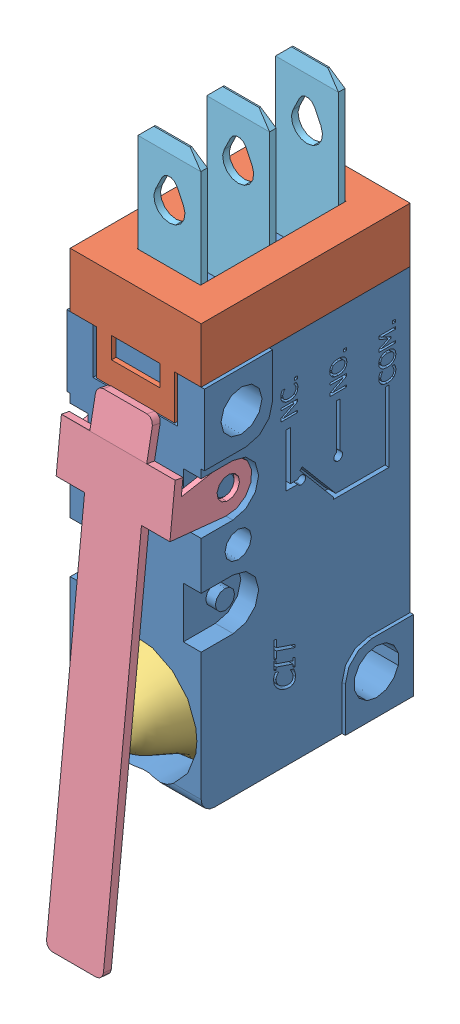
SolidWorks assembly [CIT Relay & Switch]LimitSwitch, configuration Default. Lengths in mm.
Overall size (10.4 50.82 20.74).
8 component instances, 5 part files, 0 mates.
Components (placement in the parent):
- VM3SCQF1802L03.stp-1: VM3SCQF1802L03.stp [Default] at origin size (10.4 50.82 20.74)
  - VM3_Solid Body.stp-1: VM3_Solid Body.stp [Default] at origin size (10.4 28.01 15.81)
  - VM3_End Cap2.stp-1: VM3_End Cap2.stp [Default] at (9.9 20.9587 0.9078) x (-1 0 0) z (0 0 -1) size (9.9 7.5 15.8)
  - Rubber Boot Push Button.stp-1: Rubber Boot Push Button.stp [Default] at (4.95 -6.3413 5.0935) x (-0.122747 -0.992438 0) z (0 0 1) size (9.25 9.25 6)
  - L88.stp-1: L88.stp [Default] at (9.55 7.7381 10.2524) x (0 -0.994711 0.102715) z (-1 0 0) size (35.16 6.04 8.6)
  - VM3S_TERMINAL_TEARDROP.stp-1: VM3S_TERMINAL_TEARDROP.stp [Default] at (4.95 16.5587 -0.0065) x (0 1 0) z (1 0 0) size (13 0.5 4.75)
  - VM3S_TERMINAL_TEARDROP.stp-2: VM3S_TERMINAL_TEARDROP.stp [Default] at (4.95 16.5587 5.6935) x (0 1 0) z (-1 0 0) size (13 0.5 4.75)
  - VM3S_TERMINAL_TEARDROP.stp-3: VM3S_TERMINAL_TEARDROP.stp [Default] at (4.95 16.5587 -5.2065) x (0 1 0) z (1 0 0) size (13 0.5 4.75)
